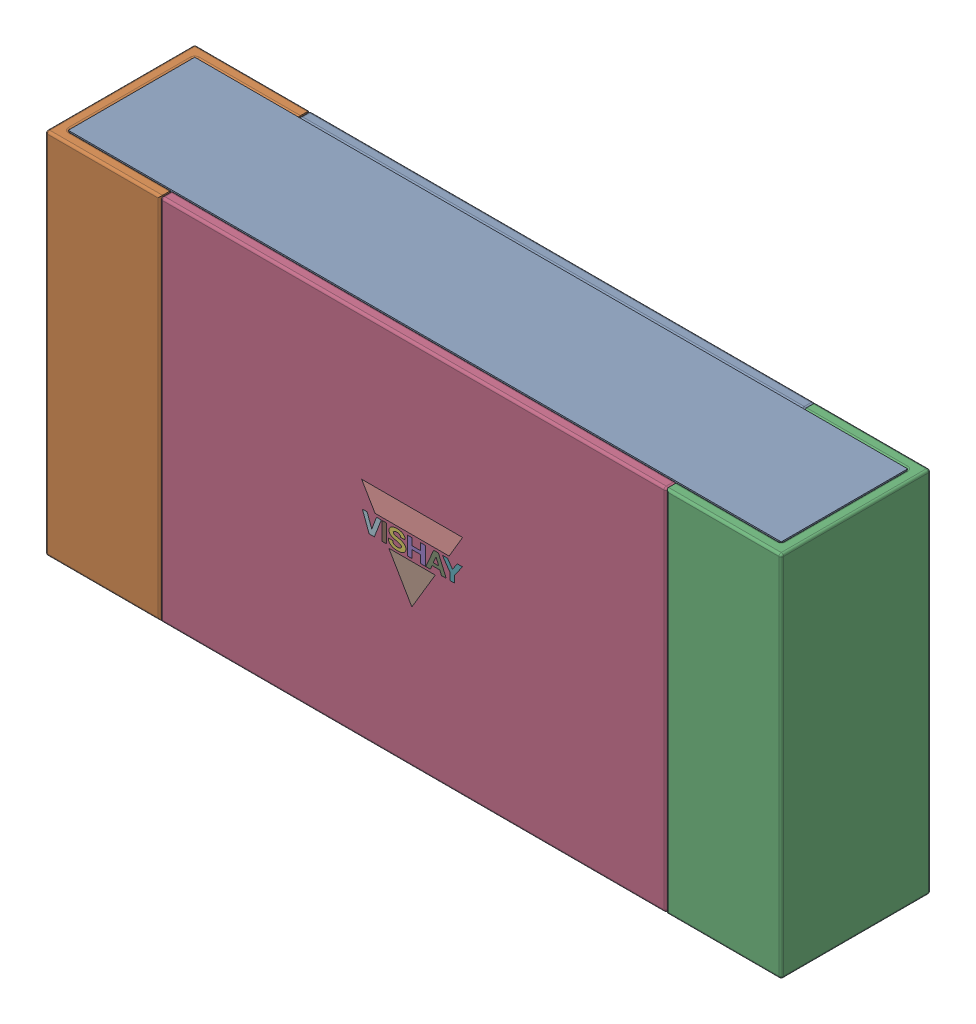
SolidWorks assembly Res_Vishay_MCA12060D1541BP100_eec, configuration Défaut. Lengths in mm.
Overall size (3.2 1.6 0.65).
6 component instances, 5 part files, 0 mates.
Components (placement in the parent):
- body-1: body [Défaut] at (0 0 0.6) x (1 0 0) z (0 0 -1) size (3.1 1.6 0.55)
- pad-1: pad [Défaut] at (-1.4133 -0.8 0.65) x (1 0 0) z (0 1 0) size (0.5 0.65 1.6)
- pad-2: pad [Défaut] at (1.4133 0.8 0.65) x (-1 0 0) z (0 -1 0) size (0.5 0.65 1.6)
- top-1: top [Défaut] at (0 0 0.65) x (1 0 0) z (0 0 -1) size (2.2 1.6 0.05)
- Vishay-1: Vishay [Défaut] at (0.0405 -0.7888 0.65) size (0.45 0.38 0.01)
- bottom-1: bottom [Défaut] at (0 0 0.05) x (1 0 0) z (0 0 -1) size (2.2 1.6 0.05)
